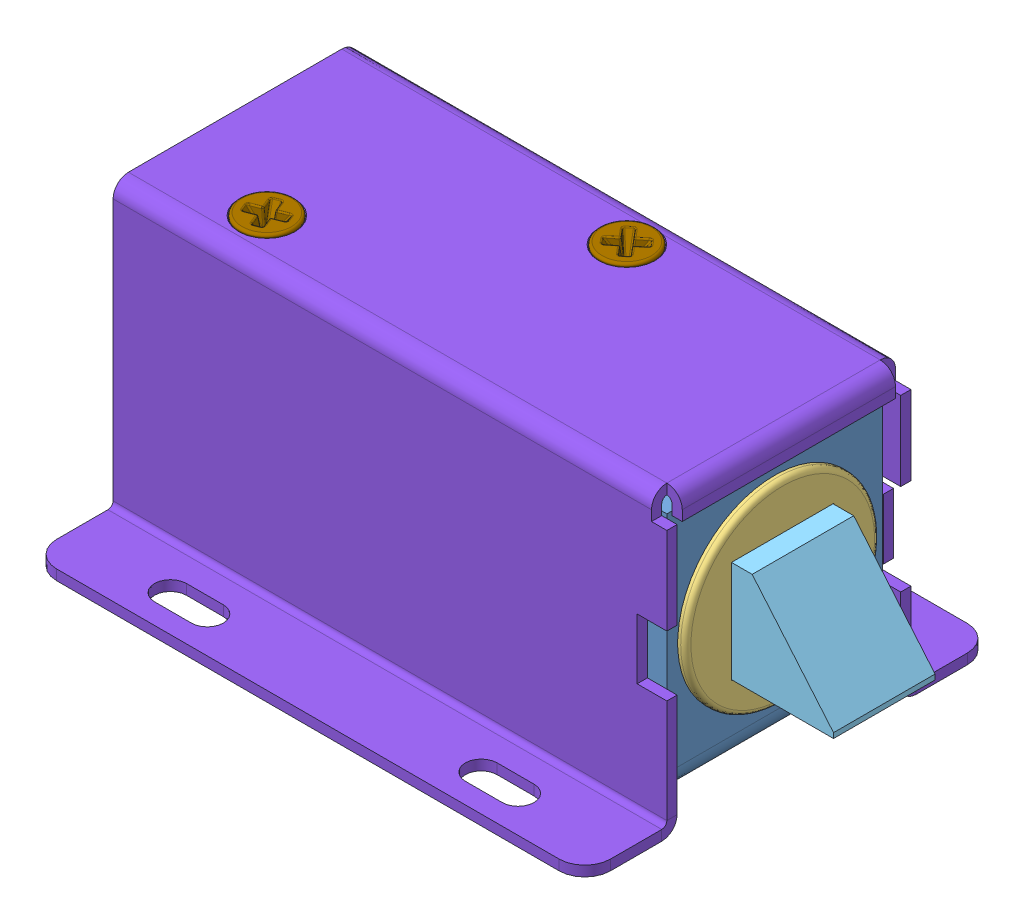
SolidWorks assembly 12V Solenoid Lock, configuration Default. Lengths in mm.
Overall size (63.92 28.75 39.8).
10 component instances, 9 part files, 24 mates.
Components (placement in the parent):
- Solenoid Casing-1: Solenoid Casing [Default] at (18.7037 22.3586 37.545) size (52.6 25.9 21)
- Shaft Guide-1: Shaft Guide [Default] at (25.8037 33.3086 37.545) x (0 0 -1) z (1 0 0) size (21 25.9 2)
- Pin Guide-1: Pin Guide [Default] at (45.8037 33.3086 37.545) x (0 0 1) z (-1 0 0) size (18.9 18.9 3.3)
- Solenoid-1: Solenoid [Default] at (24.6037 33.3086 37.545) x (0 0 1) z (-1 0 0) size (21 21 34.02)
- Shaft-1: Shaft [Default] at (13.7037 33.3086 37.545) size (42 9.9 9.9)
- Lockig Ring-1: Lockig Ring [Default] at (43.7037 33.3086 37.545) x (0 -0.117806 0.993037) z (0 -0.993037 -0.117806) size (12.2 0.9 9.93)
- Washer-1: Washer [Default] at (42.8037 33.3086 37.545) x (0 0.912967 0.408033) z (0 -0.408033 0.912967) size (15.4 0.6 15.4)
- Casing-1: Casing [Default] at (19.4037 47.2586 37.545) size (54 28.5 39.8)
- M2.7 x 4 Screw-1: M2.7 x 4 Screw [Default] at (22.8037 47.5086 29.745) x (0.767891 0 -0.640581) z (-0.640581 0 -0.767891) size (5.3 4.1 5.3)
- M2.7 x 4 Screw-2: M2.7 x 4 Screw [Default] at (2.8037 47.5086 44.845) x (-0.370169 0 -0.928964) z (-0.928964 0 0.370169) size (5.3 4.1 5.3)
Mates (geometry in assembly coordinates):
- Coincident1: coincident: plane of Solenoid Casing-1 through (18.7037 44.2586 37.545) normal (0 -1 0); plane of Shaft Guide-1 through (27.8037 44.2586 34.045) normal (0 1 0)
- Coincident2: coincident: plane of Solenoid Casing-1 through (29.2037 44.2586 41.045) normal (0 0 -1); plane of Shaft Guide-1 through (27.8037 44.2586 41.045) normal (0 0 1)
- Coincident3: coincident: plane of Solenoid Casing-1 through (25.8037 44.2586 34.045) normal (1 0 0); plane of Shaft Guide-1 through (25.8037 33.3086 37.545) normal (-1 0 0)
- Concentric1: concentric: cylinder of Solenoid Casing-1 through (43.0037 33.3086 37.545) axis (1 0 0) radius 8.25; cylinder of Pin Guide-1 through (42.5037 33.3086 37.545) axis (1 0 0) radius 8.25
- Coincident4: coincident: plane of Solenoid Casing-1 through (45.0037 22.3586 37.545) normal (1 0 0); plane of Pin Guide-1 through (45.0037 33.3086 37.545) normal (-1 0 0)
- Parallel1: parallel: plane of Shaft Guide-1 through (27.8037 22.3586 48.045) normal (0 0 1); plane of Pin Guide-1 through (42.5037 28.3086 32.545) normal (0 0 1)
- Parallel4: parallel: plane of Shaft Guide-1 through (27.8037 22.3586 48.045) normal (0 0 1); plane of Solenoid-1 through (25.8037 22.9586 47.545) normal (0 0 1)
- Coincident7: coincident: plane of Shaft Guide-1 through (25.8037 33.3086 37.545) normal (-1 0 0); plane of Solenoid-1 through (25.8037 33.3086 37.545) normal (1 0 0)
- Concentric5: concentric: cylinder of Shaft Guide-1 through (27.8037 33.3086 37.545) axis (-1 0 0) radius 4; cylinder of Solenoid-1 through (0.8037 33.3086 37.545) axis (1 0 0) radius 3.85
- Parallel5: parallel: plane of Pin Guide-1 through (42.5037 28.3086 42.545) normal (0 0 -1); plane of Shaft-1 through (55.7037 28.3586 42.495) normal (0 0 1)
- Concentric6: concentric: cylinder of Solenoid-1 through (0.8037 33.3086 37.545) axis (1 0 0) radius 3.85; cylinder of Shaft-1 through (43.7037 33.3086 37.545) axis (-1 0 0) radius 3.85
- Concentric7: concentric: cylinder of Shaft-1 through (43.7037 33.3086 37.545) axis (-1 0 0) radius 3.85; cylinder of Lockig Ring-1 through (42.8037 33.3086 37.545) axis (1 0 0) radius 6.1
- Coincident9: coincident: plane of Shaft-1 through (43.7037 33.3086 37.545) normal (-1 0 0); plane of Lockig Ring-1 through (43.7037 36.0511 34.4973) normal (1 0 0)
- Concentric8: concentric: cylinder of Shaft-1 through (43.7037 33.3086 37.545) axis (-1 0 0) radius 3.85; cylinder of Washer-1 through (42.2037 33.3086 37.545) axis (1 0 0) radius 4.1
- Coincident10: coincident: plane of Lockig Ring-1 through (42.8037 36.0511 34.4973) normal (-1 0 0); plane of Washer-1 through (42.8037 33.3086 37.545) normal (1 0 0)
- Coincident11: coincident: plane of Pin Guide-1 through (43.7037 33.3086 37.545) normal (-1 0 0); plane of Lockig Ring-1 through (43.7037 36.0511 34.4973) normal (1 0 0)
- Distance1: distance = 0.4 mm: plane of Solenoid Casing-1 through (-5.5963 46.2586 27.045) normal (0 0 -1); plane of Casing-1 through (19.4037 47.2586 26.645) normal (0 0 1)
- Coincident14: coincident: plane of Solenoid Casing-1 through (18.7037 46.2586 37.545) normal (0 1 0); plane of Casing-1 through (19.4037 46.2586 37.545) normal (0 -1 0)
- Coincident15: coincident: plane of Solenoid Casing-1 through (-7.5963 22.3586 37.545) normal (-1 0 0); plane of Casing-1 through (-7.5963 46.2586 25.645) normal (-1 0 0)
- Coincident17: coincident: circle of M2.7 x 4 Screw-1; plane of M2.7 x 4 Screw-2 through (2.8037 47.5086 44.845) normal (0 1 0)
- Concentric12: concentric: cylinder of Solenoid Casing-1 through (2.8037 44.2586 44.845) axis (0 1 0) radius 1.25; cylinder of M2.7 x 4 Screw-2 through (2.8037 43.4086 44.845) axis (0 -1 0) radius 1.375
- Concentric13: concentric: cylinder of Solenoid Casing-1 through (22.8037 44.2586 29.745) axis (0 1 0) radius 1.25; cylinder of M2.7 x 4 Screw-1 through (22.8037 43.4086 29.745) axis (0 -1 0) radius 1.375
- Parallel7: parallel: cone of Casing-1 through (2.8037 46.2586 44.845) axis (0 -1 0); cone of M2.7 x 4 Screw-2 through (2.8037 45.8086 44.845) axis (0 -1 0)
- Coincident23: coincident: plane of Casing-1 through (19.4037 47.2586 37.545) normal (0 1 0); circle of M2.7 x 4 Screw-2
